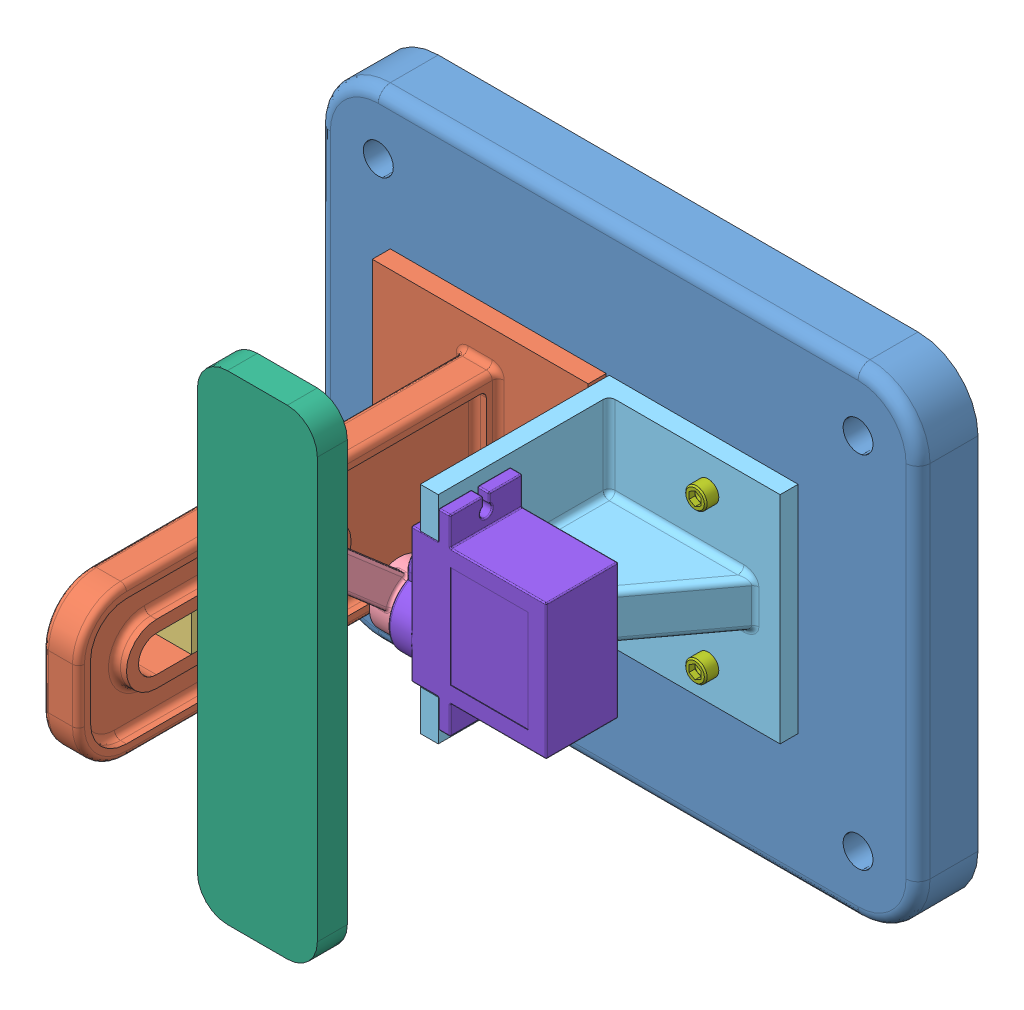
SolidWorks assembly motion study, configuration Default. Lengths in mm.
Overall size (100 80 83).
11 component instances, 8 part files, 26 mates.
Components (placement in the parent):
- Base-1: Base [Default] at (50.3077 59.1522 65.1759) size (100 80 10)
- bracket-1: bracket [Default] at (30.3077 59.1522 75.1759) size (36 36 73)
- Clip-1: Clip [Default] at (25.3077 59.1522 125.8425) x (0 0 1) z (1 0 0) size (7 10 8)
- Servo arm-1: Servo arm [Default] at (41.3077 63.7285 112.0092) x (0 0.655086 0.755554) z (1 0 0) size (38 10 4)
- Servo mount-1: Servo mount [Default] at (50.3077 77.1522 76.6759) x (1 0 0) z (0 -1 0) size (31.5 31.5 36)
- Shelf-1: Shelf [Default] at (43.3077 59.1522 128.3425) x (0 -1 0) z (0 0 -1) size (80 26 5)
- socket head cap screw_ai-1: socket head cap screw_ai [HX-SHCS 0.086-64x0.375x0.375-N] at (20.3077 59.1522 80.3603) x (0 0 -1) z (0.918496 -0.395431 0) size (11.71 3.56 3.56)
- socket head cap screw_ai-2: socket head cap screw_ai [HX-SHCS 0.086-64x0.375x0.375-N] at (40.3077 59.1522 80.3603) x (0 0 -1) z (0.635977 -0.771708 0) size (11.71 3.56 3.56)
- socket head cap screw_ai-3: socket head cap screw_ai [HX-SHCS 0.086-64x0.375x0.375-N] at (68.3077 71.6522 80.3603) x (0 0 -1) z (1 0 0) size (11.71 3.56 3.56)
- socket head cap screw_ai-4: socket head cap screw_ai [HX-SHCS 0.086-64x0.375x0.375-N] at (68.3077 46.6522 80.3603) x (0 0 -1) z (1 0 0) size (11.71 3.56 3.56)
- Micro Servo SG92R 180-1: Micro Servo SG92R 180 [Valor predeterminado] at (53.8077 59.1522 100.6759) x (0 1 0) z (0 0 1) size (32 29 12)
Mates (geometry in assembly coordinates):
- Coincident1: coincident anti-aligned: plane of Base-1 through (50.3077 59.1522 75.1759) normal (0 0 1); plane of bracket-1 through (30.3077 59.1522 75.1759) normal (0 0 -1)
- Concentric1: concentric aligned: circle of Base-1; circle of bracket-1
- Coincident3: coincident anti-aligned: plane of Base-1 through (50.3077 59.1522 75.1759) normal (0 0 1); plane of Servo mount-1 through (50.3077 41.1522 75.1759) normal (0 0 -1)
- Coincident4: coincident aligned: circle of Base-1; circle of Servo mount-1
- Coincident6: coincident anti-aligned: plane of bracket-1 through (-36.6923 56.1522 138.1759) normal (0 1 0); plane of Clip-1 through (33.3077 56.1522 129.3425) normal (0 -1 0)
- Coincident8: coincident anti-aligned: plane of bracket-1 through (27.3077 71.6522 148.1759) normal (-1 0 0); plane of Clip-1 through (27.3077 59.1522 125.8425) normal (1 0 0)
- Coincident9: coincident aligned: circle of Base-1; circle of bracket-1
- Concentric2: concentric aligned: circle of Base-1; circle of Servo mount-1
- Concentric3: concentric aligned: cylinder of bracket-1 through (20.3077 59.1522 75.1759) axis (0 0 1) radius 1.5; cylinder of socket head cap screw_ai-1 through (20.3077 59.1522 112.1103) axis (0 0 1) radius 1.0922
- Coincident11: coincident aligned: plane of bracket-1 through (30.3077 59.1522 78.1759) normal (0 0 1); circle of socket head cap screw_ai-1
- Coincident12: coincident aligned: plane of bracket-1 through (30.3077 59.1522 78.1759) normal (0 0 1); circle of socket head cap screw_ai-2
- Concentric6: concentric aligned: cylinder of bracket-1 through (40.3077 59.1522 75.1759) axis (0 0 1) radius 1.5; cylinder of socket head cap screw_ai-2 through (40.3077 59.1522 112.1103) axis (0 0 1) radius 1.0922
- Concentric7: concentric aligned: cylinder of Servo mount-1 through (68.3077 71.6522 75.1759) axis (0 0 1) radius 1.5; cylinder of socket head cap screw_ai-3 through (68.3077 71.6522 112.1103) axis (0 0 1) radius 1.0922
- Coincident13: coincident aligned: plane of Servo mount-1 through (50.3077 41.1522 78.1759) normal (0 0 1); circle of socket head cap screw_ai-3
- Coincident14: coincident anti-aligned: plane of Servo mount-1 through (50.3077 41.1522 78.1759) normal (0 0 1); plane of socket head cap screw_ai-4 through (68.3077 48.4302 78.1759) normal (0 0 -1)
- Concentric9: concentric aligned: cylinder of Servo mount-1 through (68.3077 46.6522 75.1759) axis (0 0 1) radius 1.5; cylinder of socket head cap screw_ai-4 through (68.3077 46.6522 112.1103) axis (0 0 1) radius 1.0922
- Coincident16: coincident anti-aligned: plane of Clip-1 through (27.3077 59.1522 125.8425) normal (1 0 0); plane of Shelf-1 through (27.3077 59.1522 128.3425) normal (-1 0 0)
- Coincident18: coincident anti-aligned: plane of Clip-1 through (33.3077 56.1522 128.3425) normal (0 0 -1); plane of Shelf-1 through (43.3077 59.1522 128.3425) normal (0 0 1)
- Coincident19: coincident anti-aligned: plane of Clip-1 through (33.3077 56.1522 123.3425) normal (0 0 1); plane of Shelf-1 through (43.3077 59.1522 123.3425) normal (0 0 -1)
- Coincident20: coincident anti-aligned: line of Clip-1 through (33.3077 62.1522 123.3425) axis (-1 0 0); line of Shelf-1 through (27.3077 62.1522 123.3425) axis (1 0 0)
- Coincident21: coincident anti-aligned: plane of Servo mount-1 through (58.8077 70.4022 94.6759) normal (0 0 1); plane of Micro Servo SG92R 180-1 through (69.8077 47.9022 94.6759) normal (0 0 -1)
- Coincident23: coincident anti-aligned: plane of Servo mount-1 through (51.8077 41.1522 106.6759) normal (1 0 0); plane of Micro Servo SG92R 180-1 through (51.8077 45.5272 100.6759) normal (-1 0 0)
- Concentric11: concentric anti-aligned: cylinder of Servo arm-1 through (43.3077 53.9022 100.6759) axis (-1 0 0) radius 2.25; cylinder of Micro Servo SG92R 180-1 through (40.8077 53.9022 100.6759) axis (1 0 0) radius 2.25
- Coincident24: coincident anti-aligned: plane of Servo arm-1 through (43.3077 53.9022 100.6759) normal (1 0 0); plane of Micro Servo SG92R 180-1 through (43.3077 53.9022 100.6759) normal (-1 0 0)
- Coincident26: coincident: line of Servo mount-1 through (51.8077 47.9022 106.6759) axis (-1 0 0); plane of Micro Servo SG92R 180-1 through (69.8077 47.9022 94.6759) normal (0 -1 0)
- Tangent2: tangent anti-aligned: cylinder of Servo arm-1 through (43.3077 73.5548 123.3425) axis (-1 0 0) radius 3; plane of Shelf-1 through (43.3077 59.1522 126.3425) normal (0 0 -1)
